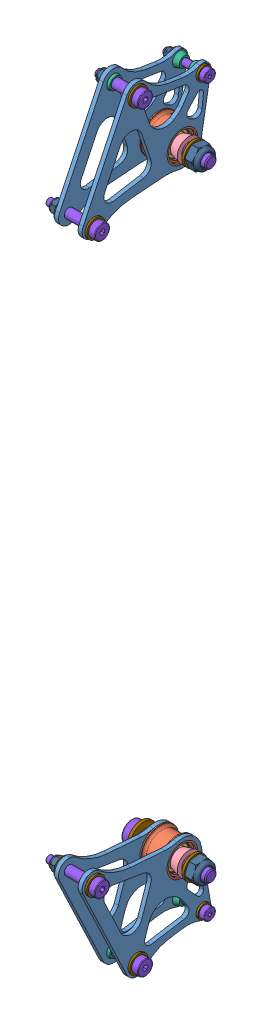
SolidWorks assembly PUTM-S-SF-DS-Rocker, configuration Domyślna. Lengths in mm.
Overall size (69 714.03 147.28).
56 component instances, 10 part files, 50 mates.
Components (placement in the parent):
- PUTM_S_SF_DS_Rockerplate-1: PUTM_S_SF_DS_Rockerplate [Default] at (14.7255 268.5661 513.4403) x (1 0 0) z (0 0.567564 0.823329) size (3.5 126.45 91.72)
- PUTM_S_SF_DS_Rockerplate-2: PUTM_S_SF_DS_Rockerplate [Default] at (35.2255 268.5661 513.4403) x (1 0 0) z (0 0.567564 0.823329) size (3.5 126.45 91.72)
- PUTM_S_SF_DS_Rockersleeve-4: PUTM_S_SF_DS_Rockersleeve [Domyślna] at (12.6854 268.5661 513.4403) x (1 0 0) z (0 0.045436 -0.998967) size (24 33 33)
- PUTM-S-SF-DS-NKIB 5901-1: PUTM-S-SF-DS-NKIB 5901 [Domyślna] at (4.6854 268.5661 513.4403) x (1 0 0) z (0 0.01484 0.99989) size (17.5 24 24)
- PUTM-S-SF-Rocker-MushRocker-5: PUTM-S-SF-Rocker-MushRocker [Domyślna] at (30.1854 268.5661 513.4403) x (-1 0 0) z (0 0.985233 0.171218) size (8 20 20)
- PUTM-S-SF-Rocker-MushRocker_long-2: PUTM-S-SF-Rocker-MushRocker_long [Domyślna] at (-4.8146 268.5661 513.4403) x (1 0 0) z (0 0 1) size (9.5 20 20)
- PUTM-S-Mush-1: PUTM-S-Mush [8x2] at (4.1854 326.5148 552.708) x (1 0 0) z (0 -0.21344 0.976956) size (2 12 12)
- PUTM-S-Mush-2: PUTM-S-Mush [8x2] at (21.1854 326.5148 552.708) x (-1 0 0) z (0 -0.11515 0.993348) size (2 12 12)
- PUTM-S-Mush-4: PUTM-S-Mush [6x4.5] at (21.1854 315.2834 495.6219) x (-1 0 0) z (0 0.027421 0.999624) size (4.5 12 12)
- PUTM-S-Mush-3: PUTM-S-Mush [6x4.5] at (4.1854 315.2834 495.6219) x (1 0 0) z (0 0 1) size (4.5 12 12)
- PUTM-S-SF-DS-Seger-1: PUTM-S-SF-DS-Seger [24 mm] at (4.6854 268.5661 513.4403) x (0 0.12945 0.991586) z (-1 0 0) size (25.2 25.11 1.2)
- PUTM-FT-ELESA_ISO7379-1: PUTM-FT-ELESA_ISO7379 [8-M6-25] at (31.7854 326.5148 552.708) x (1 0 0) z (0 0.616334 0.787485) size (41.5 13 13)
- PUTM-FT-FABORY_ISO7089-1: PUTM-FT-FABORY_ISO7089 [M8 [38093.080.001]] at (24.6854 326.5148 552.708) x (0 -0.947466 -0.319858) z (1 0 0) size (16 16 1.6)
- PUTM-FT-FABORY_ISO7089-2: PUTM-FT-FABORY_ISO7089 [M6 [38093.060.001]] at (-0.9146 326.5148 552.708) x (0 0.510535 -0.859857) z (1 0 0) size (12 12 1.6)
- PUTM-FT-FABORY_DIN985-1: PUTM-FT-FABORY_DIN985 [M6 [12348.060.001]] at (-0.9146 326.5148 552.708) x (0 0.291071 0.956701) z (-1 0 0) size (11.9 10.35 6.18)
- PUTM-FT-ELESA_ISO7379-2: PUTM-FT-ELESA_ISO7379 [6-M5-25] at (30.7854 315.2834 495.6219) x (1 0 0) z (0 0.899221 0.437495) size (39 10 10)
- PUTM-FT-FABORY_ISO7089-3: PUTM-FT-FABORY_ISO7089 [M6 [38093.060.001]] at (26.2854 315.2834 495.6219) x (0 -0.694708 -0.719291) z (-1 0 0) size (12 12 1.6)
- PUTM-FT-FABORY_ISO7089-4: PUTM-FT-FABORY_ISO7089 [M6 [38093.060.001]] at (0.6854 315.2834 495.6219) x (0 -0.008303 -0.999966) z (-1 0 0) size (12 12 1.6)
- PUTM-FT-FABORY_DIN985-2: PUTM-FT-FABORY_DIN985 [M5 [12348.050.001]] at (-0.9146 315.2834 495.6219) x (0 -0.96841 0.249362) z (-1 0 0) size (9.51 8.27 5.13)
- PUTM-FT-ELESA_ISO7379-3: PUTM-FT-ELESA_ISO7379 [8-M6-30] at (33.2854 247.2979 591.5983) x (1 0 0) z (0 -0.758212 0.652008) size (46.5 13 13)
- PUTM-FT-FABORY_ISO7089-5: PUTM-FT-FABORY_ISO7089 [M6 [38093.060.001]] at (-0.9146 247.2979 591.5983) x (0 0.756021 0.654548) z (-1 0 0) size (12 12 1.6)
- PUTM-FT-FABORY_ISO7089-6: PUTM-FT-FABORY_ISO7089 [M8 [38093.080.001]] at (26.1854 247.2979 591.5983) x (0 0.88573 0.464201) z (1 0 0) size (16 16 1.6)
- PUTM-FT-FABORY_DIN985-3: PUTM-FT-FABORY_DIN985 [M6 [12348.060.001]] at (-2.5146 247.2979 591.5983) x (0 0.369355 -0.929288) z (-1 0 0) size (11.9 10.35 6.18)
- PUTM-FT-ELESA_ISO7379-10: PUTM-FT-ELESA_ISO7379 [12-M10-45] at (-19.3146 268.5661 513.4403) x (-1 0 0) z (0 0.653245 0.757146) size (69 18 18)
- PUTM-FT-FABORY_ISO7089-19: PUTM-FT-FABORY_ISO7089 [M12 [38093.120.001]] at (-8.8146 268.5661 513.4403) x (0 0.487973 0.872859) z (-1 0 0) size (24 24 2.5)
- PUTM-FT-FABORY_ISO7089-20: PUTM-FT-FABORY_ISO7089 [M10 [38093.100.001]] at (36.1854 268.5661 513.4403) x (0 -0.102877 0.994694) z (-1 0 0) size (20 20 2)
- PUTM-FT-FABORY_DIN985-10: PUTM-FT-FABORY_DIN985 [M10 [12348.100.001]] at (36.1854 268.5661 513.4403) x (0 -0.924225 -0.381849) z (1 0 0) size (20.27 17.64 10.37)
- PUTM-FT-FABORY_ISO7089-23: PUTM-FT-FABORY_ISO7089 [M8 [38093.080.001]] at (0.6854 247.2979 591.5983) x (0 0.385787 0.922588) z (-1 0 0) size (16 16 1.6)
- PUTM-S-SF-DS-Seger-2: PUTM-S-SF-DS-Seger [24 mm] at (3.4854 -268.5661 513.4403) x (0 -0.12945 0.991586) z (1 0 0) size (25.2 25.11 1.2)
- PUTM-S-SF-DS-NKIB 5901-2: PUTM-S-SF-DS-NKIB 5901 [Domyślna] at (4.6854 -268.5661 513.4403) x (1 0 0) z (0 0.01484 -0.99989) size (17.5 24 24)
- PUTM-S-Mush-9: PUTM-S-Mush [8x2] at (21.1854 -326.5148 552.708) x (-1 0 0) z (0 -0.11515 -0.993348) size (2 12 12)
- PUTM_S_SF_DS_Rockersleeve-6: PUTM_S_SF_DS_Rockersleeve [Domyślna] at (12.6854 -268.5661 513.4403) x (1 0 0) z (0 0.045436 0.998967) size (24 33 33)
- PUTM-S-Mush-10: PUTM-S-Mush [6x4.5] at (21.1854 -315.2834 495.6219) x (-1 0 0) z (0 0.027421 -0.999624) size (4.5 12 12)
- PUTM-S-Mush-11: PUTM-S-Mush [6x4.5] at (4.1854 -315.2834 495.6219) x (1 0 0) z (0 0 -1) size (4.5 12 12)
- PUTM-S-Mush-12: PUTM-S-Mush [8x2] at (4.1854 -326.5148 552.708) x (1 0 0) z (0 -0.21344 -0.976956) size (2 12 12)
- PUTM-FT-ELESA_ISO7379-7: PUTM-FT-ELESA_ISO7379 [8-M6-30] at (33.2854 -247.2979 591.5983) x (1 0 0) z (0 -0.758212 -0.652008) size (46.5 13 13)
- PUTM-FT-FABORY_ISO7089-13: PUTM-FT-FABORY_ISO7089 [M6 [38093.060.001]] at (24.6854 -315.2834 495.6219) x (0 0.694708 -0.719291) z (1 0 0) size (12 12 1.6)
- PUTM-FT-FABORY_ISO7089-14: PUTM-FT-FABORY_ISO7089 [M6 [38093.060.001]] at (0.6854 -326.5148 552.708) x (0 -0.510535 -0.859857) z (-1 0 0) size (12 12 1.6)
- PUTM-FT-FABORY_DIN985-7: PUTM-FT-FABORY_DIN985 [M6 [12348.060.001]] at (-0.9146 -326.5148 552.708) x (0 0.291071 -0.956701) z (-1 0 0) size (11.9 10.35 6.18)
- PUTM-FT-FABORY_ISO7089-15: PUTM-FT-FABORY_ISO7089 [M6 [38093.060.001]] at (-2.5146 -247.2979 591.5983) x (0 -0.756021 0.654548) z (1 0 0) size (12 12 1.6)
- PUTM-FT-FABORY_DIN985-8: PUTM-FT-FABORY_DIN985 [M5 [12348.050.001]] at (-0.9146 -315.2834 495.6219) x (0 -0.96841 -0.249362) z (-1 0 0) size (9.51 8.27 5.13)
- PUTM-FT-ELESA_ISO7379-8: PUTM-FT-ELESA_ISO7379 [8-M6-25] at (31.7854 -326.5148 552.708) x (1 0 0) z (0 0.616334 -0.787485) size (41.5 13 13)
- PUTM-FT-ELESA_ISO7379-9: PUTM-FT-ELESA_ISO7379 [6-M5-25] at (30.7854 -315.2834 495.6219) x (1 0 0) z (0 0.899221 -0.437495) size (39 10 10)
- PUTM_S_SF_DS_Rockerplate-5: PUTM_S_SF_DS_Rockerplate [Default] at (10.6453 -268.5661 513.4403) x (-1 0 0) z (0 -0.567564 0.823329) size (3.5 126.45 91.72)
- PUTM-FT-FABORY_DIN985-9: PUTM-FT-FABORY_DIN985 [M6 [12348.060.001]] at (-2.5146 -247.2979 591.5983) x (0 0.369355 0.929288) z (-1 0 0) size (11.9 10.35 6.18)
- PUTM-FT-FABORY_ISO7089-16: PUTM-FT-FABORY_ISO7089 [M8 [38093.080.001]] at (27.7854 -247.2979 591.5983) x (0 -0.88573 0.464201) z (-1 0 0) size (16 16 1.6)
- PUTM-FT-FABORY_ISO7089-17: PUTM-FT-FABORY_ISO7089 [M6 [38093.060.001]] at (-0.9146 -315.2834 495.6219) x (0 0.008303 -0.999966) z (1 0 0) size (12 12 1.6)
- PUTM-FT-FABORY_ISO7089-18: PUTM-FT-FABORY_ISO7089 [M8 [38093.080.001]] at (26.2854 -326.5148 552.708) x (0 0.947466 -0.319858) z (-1 0 0) size (16 16 1.6)
- PUTM_S_SF_DS_Rockerplate-6: PUTM_S_SF_DS_Rockerplate [Default] at (-9.8547 -268.5661 513.4403) x (-1 0 0) z (0 -0.567564 0.823329) size (3.5 126.45 91.72)
- PUTM-FT-ELESA_ISO7379-11: PUTM-FT-ELESA_ISO7379 [12-M10-45] at (-19.3146 -268.5661 513.4403) x (-1 0 0) z (0 0.653245 -0.757146) size (69 18 18)
- PUTM-FT-FABORY_ISO7089-21: PUTM-FT-FABORY_ISO7089 [M12 [38093.120.001]] at (-11.3146 -268.5661 513.4403) x (0 -0.487973 0.872859) z (1 0 0) size (24 24 2.5)
- PUTM-FT-FABORY_ISO7089-22: PUTM-FT-FABORY_ISO7089 [M10 [38093.100.001]] at (34.1854 -268.5661 513.4403) x (0 0.102877 0.994694) z (1 0 0) size (20 20 2)
- PUTM-FT-FABORY_DIN985-11: PUTM-FT-FABORY_DIN985 [M10 [12348.100.001]] at (36.1854 -268.5661 513.4403) x (0 -0.924225 0.381849) z (1 0 0) size (20.27 17.64 10.37)
- PUTM-S-SF-Rocker-MushRocker_long-4: PUTM-S-SF-Rocker-MushRocker_long [Domyślna] at (-4.8146 -268.5661 513.4403) x (1 0 0) z (0 0 -1) size (9.5 20 20)
- PUTM-S-SF-Rocker-MushRocker-6: PUTM-S-SF-Rocker-MushRocker [Domyślna] at (30.1854 -268.5661 513.4403) x (-1 0 0) z (0 0.985233 -0.171218) size (8 20 20)
- PUTM-FT-FABORY_ISO7089-24: PUTM-FT-FABORY_ISO7089 [M8 [38093.080.001]] at (-0.9146 -247.2979 591.5983) x (0 -0.385787 0.922588) z (1 0 0) size (16 16 1.6)
Mates (geometry in assembly coordinates):
- Koncentryczne37: concentric aligned: cylinder of PUTM_S_SF_DS_Rockerplate-1 through (4.1854 268.5661 513.4403) axis (-1 0 0) radius 13.35; cylinder of PUTM_S_SF_DS_Rockersleeve-4 through (5.6834 268.5661 513.4403) axis (-1 0 0) radius 13.35
- Koncentryczne38: concentric aligned: cylinder of PUTM_S_SF_DS_Rockerplate-2 through (24.6854 268.5661 513.4403) axis (-1 0 0) radius 13.35; cylinder of PUTM_S_SF_DS_Rockersleeve-4 through (5.6834 268.5661 513.4403) axis (-1 0 0) radius 13.35
- Wspólnie49: coincident anti-aligned: plane of PUTM_S_SF_DS_Rockerplate-1 through (4.1854 268.5661 513.4403) normal (1 0 0); plane of PUTM_S_SF_DS_Rockersleeve-4 through (4.1854 255.2299 512.8338) normal (-1 0 0)
- Koncentryczne39: concentric aligned: cylinder of PUTM_S_SF_DS_Rockerplate-1 through (4.1854 247.2979 591.5983) axis (-1 0 0) radius 4; cylinder of PUTM_S_SF_DS_Rockerplate-2 through (24.6854 247.2979 591.5983) axis (-1 0 0) radius 4
- Wspólnie54: coincident anti-aligned: plane of PUTM_S_SF_DS_Rockerplate-2 through (21.1854 268.5661 513.4403) normal (-1 0 0); plane of PUTM_S_SF_DS_Rockersleeve-4 through (21.1854 255.2299 512.8338) normal (1 0 0)
- Wspólnie56: coincident anti-aligned: plane of PUTM_S_SF_DS_Rockerplate-1 through (4.1854 268.5661 513.4403) normal (1 0 0); plane of PUTM-S-Mush-1 through (4.1854 332.3766 553.9886) normal (-1 0 0)
- Wspólnie58: coincident anti-aligned: plane of PUTM_S_SF_DS_Rockerplate-2 through (21.1854 268.5661 513.4403) normal (-1 0 0); plane of PUTM-S-Mush-2 through (21.1854 320.5547 552.0171) normal (1 0 0)
- Wspólnie64: coincident anti-aligned: plane of PUTM-FT-ELESA_ISO7379-2 through (26.2854 317.4708 491.1258) normal (-1 0 0); plane of PUTM-FT-FABORY_ISO7089-3 through (26.2854 315.2834 495.6219) normal (1 0 0)
- Wspólnie66: coincident anti-aligned: plane of PUTM_S_SF_DS_Rockerplate-1 through (4.1854 268.5661 513.4403) normal (1 0 0); plane of PUTM-S-Mush-3 through (4.1854 321.2834 495.6219) normal (-1 0 0)
- Wspólnie68: coincident anti-aligned: plane of PUTM_S_SF_DS_Rockerplate-2 through (21.1854 268.5661 513.4403) normal (-1 0 0); plane of PUTM-S-Mush-4 through (21.1854 309.2856 495.7864) normal (1 0 0)
- Wspólnie70: coincident anti-aligned: plane of PUTM-FT-FABORY_ISO7089-4 through (-0.9146 315.2834 495.6219) normal (-1 0 0); plane of PUTM-FT-FABORY_DIN985-2 through (-0.9146 315.2834 495.6219) normal (1 0 0)
- Koncentryczne54: concentric aligned: cylinder of PUTM_S_SF_DS_Rockersleeve-4 through (5.6834 268.5661 513.4403) axis (-1 0 0) radius 12; cylinder of PUTM-S-SF-DS-NKIB 5901-1 through (20.6854 268.5661 513.4403) axis (-1 0 0) radius 12
- Wspólnie75: coincident anti-aligned: plane of PUTM_S_SF_DS_Rockersleeve-4 through (20.6854 256.5785 512.8951) normal (-1 0 0); plane of PUTM-S-SF-DS-NKIB 5901-1 through (20.6854 278.565 513.2919) normal (1 0 0)
- Koncentryczne55: concentric anti-aligned: cylinder of PUTM_S_SF_DS_Rockersleeve-4 through (5.6834 268.5661 513.4403) axis (-1 0 0) radius 12.6; cylinder of PUTM-S-SF-DS-Seger-1 through (3.4854 268.5661 513.4403) axis (1 0 0) radius 12.6
- Wspólnie77: coincident anti-aligned: plane of PUTM-S-SF-DS-NKIB 5901-1 through (4.6854 280.2648 513.2667) normal (-1 0 0); plane of PUTM-S-SF-DS-Seger-1 through (4.6854 268.5661 513.4403) normal (1 0 0)
- Koncentryczne57: concentric aligned: line of PUTM_S_SF_DS_Rockerplate-2 through (24.6854 326.5148 552.708) axis (-1 0 0); cylinder of PUTM-FT-ELESA_ISO7379-1 through (31.7854 326.5148 552.708) axis (-1 0 0) radius 4
- Koncentryczne58: concentric aligned: cylinder of PUTM-FT-ELESA_ISO7379-1 through (31.7854 326.5148 552.708) axis (-1 0 0) radius 4; line of PUTM-FT-FABORY_ISO7089-1 through (26.2854 326.5148 552.708) axis (-1 0 0)
- Wspólnie79: coincident anti-aligned: plane of PUTM_S_SF_DS_Rockerplate-2 through (24.6854 268.5661 513.4403) normal (1 0 0); plane of PUTM-FT-FABORY_ISO7089-1 through (24.6854 326.5148 552.708) normal (-1 0 0)
- Koncentryczne62: concentric aligned: circle of PUTM-FT-ELESA_ISO7379-1; cylinder of PUTM-FT-FABORY_ISO7089-2 through (0.6854 326.5148 552.708) axis (-1 0 0) radius 3.2
- Wspólnie80: coincident anti-aligned: plane of PUTM_S_SF_DS_Rockerplate-1 through (0.6854 268.5661 513.4403) normal (-1 0 0); plane of PUTM-FT-FABORY_ISO7089-2 through (0.6854 326.5148 552.708) normal (1 0 0)
- Koncentryczne63: concentric anti-aligned: cylinder of PUTM-FT-ELESA_ISO7379-1 through (31.7854 326.5148 552.708) axis (-1 0 0) radius 3; cylinder of PUTM-FT-FABORY_DIN985-1 through (-4.9146 326.5148 552.708) axis (1 0 0) radius 3
- Wspólnie81: coincident anti-aligned: plane of PUTM-FT-FABORY_ISO7089-2 through (-0.9146 326.5148 552.708) normal (-1 0 0); plane of PUTM-FT-FABORY_DIN985-1 through (-0.9146 326.5148 552.708) normal (1 0 0)
- Koncentryczne66: concentric aligned: cylinder of PUTM-FT-ELESA_ISO7379-2 through (30.7854 315.2834 495.6219) axis (-1 0 0) radius 3; circle of PUTM-FT-FABORY_ISO7089-3
- Koncentryczne67: concentric aligned: cylinder of PUTM-FT-FABORY_ISO7089-4 through (-0.9146 315.2834 495.6219) axis (1 0 0) radius 3.2; cylinder of PUTM-FT-FABORY_DIN985-2 through (-4.1146 315.2834 495.6219) axis (1 0 0) radius 2.5
- Koncentryczne68: concentric anti-aligned: cylinder of PUTM-FT-ELESA_ISO7379-2 through (30.7854 315.2834 495.6219) axis (-1 0 0) radius 3; cylinder of PUTM-S-Mush-4 through (21.1854 315.2834 495.6219) axis (1 0 0) radius 3
- Koncentryczne69: concentric aligned: cylinder of PUTM_S_SF_DS_Rockerplate-2 through (24.6854 315.2834 495.6219) axis (-1 0 0) radius 3; cylinder of PUTM-FT-ELESA_ISO7379-2 through (30.7854 315.2834 495.6219) axis (-1 0 0) radius 3
- Wspólnie82: coincident anti-aligned: plane of PUTM_S_SF_DS_Rockerplate-2 through (24.6854 268.5661 513.4403) normal (1 0 0); plane of PUTM-FT-FABORY_ISO7089-3 through (24.6854 315.2834 495.6219) normal (-1 0 0)
- Koncentryczne70: concentric anti-aligned: cylinder of PUTM-FT-ELESA_ISO7379-2 through (30.7854 315.2834 495.6219) axis (-1 0 0) radius 2.5; cylinder of PUTM-FT-FABORY_ISO7089-4 through (-0.9146 315.2834 495.6219) axis (1 0 0) radius 3.2
- Wspólnie83: coincident anti-aligned: plane of PUTM_S_SF_DS_Rockerplate-1 through (0.6854 268.5661 513.4403) normal (-1 0 0); plane of PUTM-FT-FABORY_ISO7089-4 through (0.6854 315.2834 495.6219) normal (1 0 0)
- Koncentryczne71: concentric aligned: cylinder of PUTM-FT-ELESA_ISO7379-3 through (33.2854 247.2979 591.5983) axis (-1 0 0) radius 4; cylinder of PUTM-FT-FABORY_ISO7089-6 through (27.7854 247.2979 591.5983) axis (-1 0 0) radius 4.2
- Koncentryczne72: concentric aligned: cylinder of PUTM_S_SF_DS_Rockerplate-2 through (24.6854 247.2979 591.5983) axis (-1 0 0) radius 4; cylinder of PUTM-FT-ELESA_ISO7379-3 through (33.2854 247.2979 591.5983) axis (-1 0 0) radius 4
- Koncentryczne74: concentric aligned: cylinder of PUTM-FT-FABORY_ISO7089-5 through (-2.5146 247.2979 591.5983) axis (1 0 0) radius 3.2; cylinder of PUTM-FT-FABORY_DIN985-3 through (-6.5146 247.2979 591.5983) axis (1 0 0) radius 3
- Wspólnie86: coincident anti-aligned: plane of PUTM-FT-FABORY_ISO7089-5 through (-2.5146 247.2979 591.5983) normal (-1 0 0); plane of PUTM-FT-FABORY_DIN985-3 through (-2.5146 247.2979 591.5983) normal (1 0 0)
- Koncentryczne76: concentric anti-aligned: cylinder of PUTM-FT-ELESA_ISO7379-3 through (33.2854 247.2979 591.5983) axis (-1 0 0) radius 3; cylinder of PUTM-FT-FABORY_DIN985-3 through (-6.5146 247.2979 591.5983) axis (1 0 0) radius 3
- Koncentryczne77: concentric anti-aligned: cylinder of PUTM-S-SF-DS-NKIB 5901-1 through (20.6854 268.5661 513.4403) axis (-1 0 0) radius 6; cylinder of PUTM-FT-ELESA_ISO7379-10 through (-19.3146 268.5661 513.4403) axis (1 0 0) radius 6
- Koncentryczne78: concentric aligned: cylinder of PUTM-FT-ELESA_ISO7379-10 through (-19.3146 268.5661 513.4403) axis (1 0 0) radius 6; cylinder of PUTM-FT-FABORY_ISO7089-19 through (-11.3146 268.5661 513.4403) axis (1 0 0) radius 6.5
- Wspólnie88: coincident anti-aligned: plane of PUTM-FT-ELESA_ISO7379-10 through (-11.3146 261.7518 519.3195) normal (1 0 0); plane of PUTM-FT-FABORY_ISO7089-19 through (-11.3146 268.5661 513.4403) normal (-1 0 0)
- Odległość1: distance = 21.5 mm: plane of PUTM-FT-FABORY_ISO7089-19 through (-8.8146 268.5661 513.4403) normal (1 0 0); point of PUTM_S_SF_DS_Rockersleeve-4
- Koncentryczne79: concentric aligned: cylinder of PUTM-FT-ELESA_ISO7379-10 through (-19.3146 268.5661 513.4403) axis (1 0 0) radius 5; cylinder of PUTM-FT-FABORY_ISO7089-20 through (34.1854 268.5661 513.4403) axis (1 0 0) radius 5.25
- Odległość2: distance = 21.5 mm: plane of PUTM-FT-FABORY_ISO7089-20 through (34.1854 268.5661 513.4403) normal (-1 0 0); point of PUTM_S_SF_DS_Rockersleeve-4
- Koncentryczne80: concentric anti-aligned: cylinder of PUTM-FT-ELESA_ISO7379-10 through (-19.3146 268.5661 513.4403) axis (1 0 0) radius 5; cylinder of PUTM-FT-FABORY_DIN985-10 through (42.6854 268.5661 513.4403) axis (-1 0 0) radius 5
- Wspólnie91: coincident anti-aligned: plane of PUTM-FT-FABORY_ISO7089-20 through (36.1854 268.5661 513.4403) normal (1 0 0); plane of PUTM-FT-FABORY_DIN985-10 through (36.1854 268.5661 513.4403) normal (-1 0 0)
- Odległość4: distance = 1.5 mm anti-aligned: plane of PUTM_S_SF_DS_Rockerplate-2 through (24.6854 268.5661 513.4403) normal (1 0 0); plane of PUTM-FT-FABORY_ISO7089-6 through (26.1854 247.2979 591.5983) normal (-1 0 0)
- Koncentryczne82: concentric anti-aligned: cylinder of PUTM-FT-ELESA_ISO7379-10 through (-19.3146 268.5661 513.4403) axis (1 0 0) radius 6; cylinder of PUTM-S-SF-Rocker-MushRocker_long-2 through (-4.8146 268.5661 513.4403) axis (-1 0 0) radius 6
- Wspólnie94: coincident anti-aligned: plane of PUTM-S-SF-DS-NKIB 5901-1 through (4.6854 276.5652 513.3216) normal (-1 0 0); plane of PUTM-S-SF-Rocker-MushRocker_long-2 through (4.6854 276.5661 513.4403) normal (1 0 0)
- Koncentryczne83: concentric anti-aligned: cylinder of PUTM-FT-ELESA_ISO7379-3 through (33.2854 247.2979 591.5983) axis (-1 0 0) radius 4; cylinder of PUTM-FT-FABORY_ISO7089-23 through (-0.9146 247.2979 591.5983) axis (1 0 0) radius 4.2
- Wspólnie95: coincident anti-aligned: plane of PUTM_S_SF_DS_Rockerplate-1 through (0.6854 268.5661 513.4403) normal (-1 0 0); plane of PUTM-FT-FABORY_ISO7089-23 through (0.6854 247.2979 591.5983) normal (1 0 0)
- Wspólnie96: coincident anti-aligned: plane of PUTM-FT-FABORY_ISO7089-5 through (-0.9146 247.2979 591.5983) normal (1 0 0); plane of PUTM-FT-FABORY_ISO7089-23 through (-0.9146 247.2979 591.5983) normal (-1 0 0)
- Koncentryczne84: concentric aligned: cylinder of PUTM-FT-ELESA_ISO7379-10 through (-19.3146 268.5661 513.4403) axis (1 0 0) radius 6; circle of PUTM-S-SF-Rocker-MushRocker-5
- Wspólnie99: coincident anti-aligned: plane of PUTM-S-SF-DS-NKIB 5901-1 through (22.1854 274.8654 513.3468) normal (1 0 0); plane of PUTM-S-SF-Rocker-MushRocker-5 through (22.1854 267.1964 521.3222) normal (-1 0 0)
